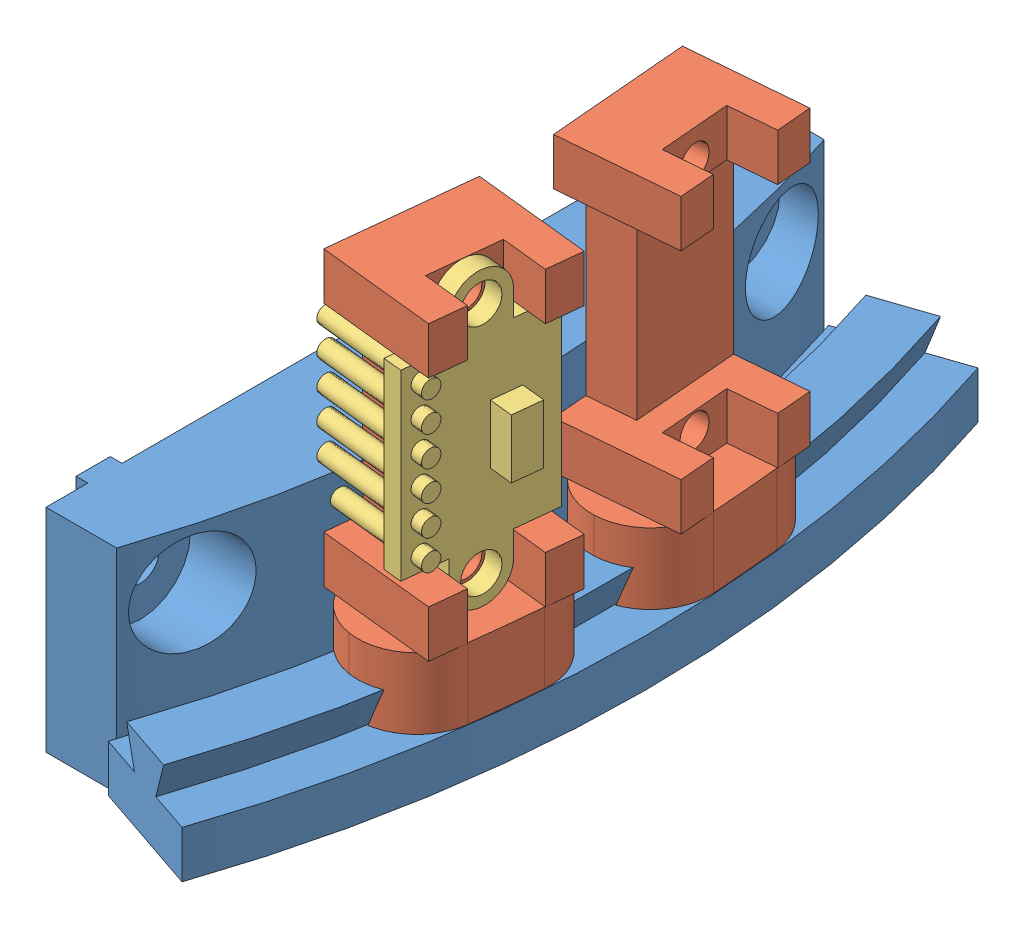
SolidWorks assembly tofSupportAssembly, configuration Default. Lengths in mm.
Overall size (100 34.8 100).
4 component instances, 3 part files, 9 mates.
Components (placement in the parent):
- Vl530xSupport-1: Vl530xSupport [Default] at (-71.557 41.8738 68.122) size (100 18 100)
- TofSupport-1: TofSupport [Default] at (-121.3617 51.8738 62.8047) x (-0.10616 0 0.994349) z (-0.994349 0 -0.10616) size (15.71 30.8 10.03)
- CJVL53L0XV2-1: CJVL53L0XV2 [Default] at (28.785 64.2738 78.8349) x (0 -1 0) z (0.994349 0 0.10616) size (24.8 12.4 11)
- TofSupport-2: TofSupport [Default] at (-121.4599 51.8738 72.3847) x (0.085109 0 0.996372) z (-0.996372 0 0.085109) size (15.71 30.8 10.03)
Mates (geometry in assembly coordinates):
- Coincident25: coincident anti-aligned: plane of Vl530xSupport-1 through (27.8707 45.8738 34.3709) normal (0 1 0); plane of TofSupport-1 through (28.234 45.8738 86.75) normal (0 -1 0)
- Coincident26: coincident: circle of Vl530xSupport-1; point of TofSupport-1
- Coincident27: coincident: circle of Vl530xSupport-1; point of TofSupport-1
- Concentric7: concentric aligned: cylinder of TofSupport-1 through (32.7624 74.1738 79.2595) axis (-0.994349 0 -0.10616) radius 1.35; cylinder of CJVL53L0XV2-1 through (30.3759 74.1738 79.0047) axis (-0.994349 0 -0.10616) radius 1.6
- Coincident28: coincident anti-aligned: plane of TofSupport-1 through (28.785 51.8738 78.8349) normal (0.994349 0 0.10616); plane of CJVL53L0XV2-1 through (28.785 74.1738 78.8349) normal (-0.994349 0 -0.10616)
- Concentric8: concentric aligned: cylinder of TofSupport-1 through (32.7624 54.3738 79.2595) axis (-0.994349 0 -0.10616) radius 1.35; cylinder of CJVL53L0XV2-1 through (30.3759 54.3738 79.0047) axis (-0.994349 0 -0.10616) radius 1.6
- Coincident29: coincident anti-aligned: plane of Vl530xSupport-1 through (27.8707 45.8738 34.3709) normal (0 1 0); plane of TofSupport-2 through (29.9584 45.8738 67.4085) normal (0 -1 0)
- Coincident30: coincident: circle of Vl530xSupport-1; point of TofSupport-2
- Coincident31: coincident: circle of Vl530xSupport-1; point of TofSupport-2
